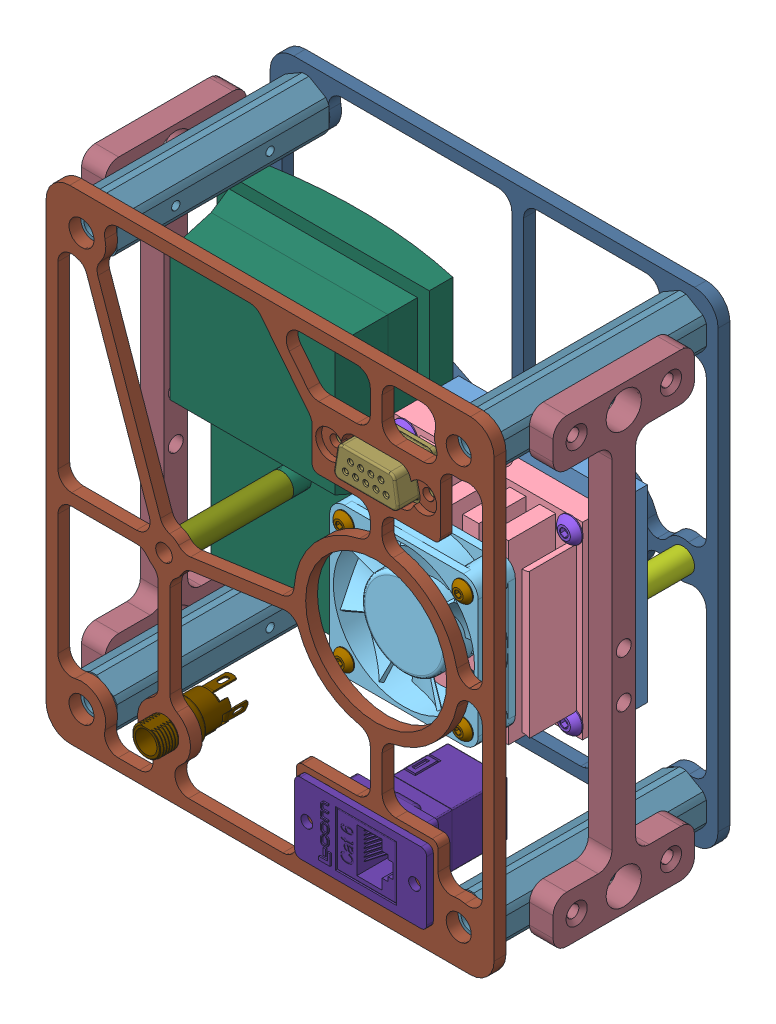
SolidWorks assembly Camera Module-Axis, configuration Default. Lengths in mm.
Overall size (127 130.18 68.59).
31 component instances, 18 part files, 40 mates.
Components (placement in the parent):
- Retina Fucker-1: Retina Fucker [Default] at (41.7658 96.3221 44.3342) x (-1 0 0) z (0 -1 0) size (51.1 57 52.54)
  - LED Interface Plate-1: LED Interface Plate [Default] at (13.1908 22.1092 31.2346) size (50.8 6.35 52.39)
  - Peltier Junction-1: Peltier Junction [Default] at (13.1908 17.3467 31.2346) size (39.69 4.76 39.69)
  - LZ4-40G108-0000-1: LZ4-40G108-0000 [Default] at (13.1908 28.4592 31.2346) size (19.46 5.4 19.4)
  - Heatsink-1: Heatsink [Default] at (13.1948 17.3467 31.2346) x (0 0 -1) z (-1 0 0) size (50.8 19.05 50.8)
  - 1939K170_DC EQUIPMENT COOLING FAN-1: 1939K170_DC EQUIPMENT COOLING FAN [Default] at (13.1908 -1.7033 31.2346) x (-0.000125 0 1) z (0 -1 0) size (40 40 10.64)
  - Reflector-1: Reflector [Default] at (13.1908 30.2092 31.2346) x (0.991681 0 -0.128723) z (0.128723 0 0.991681) size (16.67 13.5 16.67)
  - Front Mounting Spacer-1: Front Mounting Spacer [Default] at (-9.0342 28.4592 31.2346) x (1 0 0) z (0 1 0) size (6.35 6.35 12.7)
  - Front Mounting Spacer-2: Front Mounting Spacer [Default] at (13.1908 28.4592 53.4596) x (1 0 0) z (0 1 0) size (6.35 6.35 12.7)
  - Front Mounting Spacer-3: Front Mounting Spacer [Default] at (35.4158 28.4592 31.2346) x (1 0 0) z (0 1 0) size (6.35 6.35 12.7)
  - 91255A150_ALLOY STEEL BUTTON-HEAD SOCKET CAP SCREW 6-32 5_8-1: 91255A150_ALLOY STEEL BUTTON-HEAD SOCKET CAP SCREW 6-32 5_8 [91255A150] at (-9.0302 9.1425 9.0096) x (1 0 0) z (0 -1 0) size (6.65 6.65 18.16)
  - 91255A150_ALLOY STEEL BUTTON-HEAD SOCKET CAP SCREW 6-32 5_8-2: 91255A150_ALLOY STEEL BUTTON-HEAD SOCKET CAP SCREW 6-32 5_8 [91255A150] at (-9.0302 9.1425 53.4596) x (1 0 0) z (0 -1 0) size (6.65 6.65 18.16)
  - 91255A150_ALLOY STEEL BUTTON-HEAD SOCKET CAP SCREW 6-32 5_8-3: 91255A150_ALLOY STEEL BUTTON-HEAD SOCKET CAP SCREW 6-32 5_8 [91255A150] at (35.4198 9.1425 53.4596) x (1 0 0) z (0 -1 0) size (6.65 6.65 18.16)
  - 91255A150_ALLOY STEEL BUTTON-HEAD SOCKET CAP SCREW 6-32 5_8-4: 91255A150_ALLOY STEEL BUTTON-HEAD SOCKET CAP SCREW 6-32 5_8 [91255A150] at (35.4198 9.1425 9.0096) x (1 0 0) z (0 -1 0) size (6.65 6.65 18.16)
  - 91255A110_ALLOY STEEL BUTTON-HEAD SOCKET CAP SCREW 4-40 1_2-1: 91255A110_ALLOY STEEL BUTTON-HEAD SOCKET CAP SCREW 4-40 1_2 [91255A110] at (29.1928 -13.2019 15.2366) x (1 0 0) z (0 -1 0) size (5.41 5.41 14.54)
  - 91255A110_ALLOY STEEL BUTTON-HEAD SOCKET CAP SCREW 4-40 1_2-2: 91255A110_ALLOY STEEL BUTTON-HEAD SOCKET CAP SCREW 4-40 1_2 [91255A110] at (-2.8072 -13.2019 15.2326) x (1 0 0) z (0 -1 0) size (5.41 5.41 14.54)
  - 91255A110_ALLOY STEEL BUTTON-HEAD SOCKET CAP SCREW 4-40 1_2-3: 91255A110_ALLOY STEEL BUTTON-HEAD SOCKET CAP SCREW 4-40 1_2 [91255A110] at (29.1888 -13.2019 47.2366) x (1 0 0) z (0 -1 0) size (5.41 5.41 14.54)
  - 91255A110_ALLOY STEEL BUTTON-HEAD SOCKET CAP SCREW 4-40 1_2-4: 91255A110_ALLOY STEEL BUTTON-HEAD SOCKET CAP SCREW 4-40 1_2 [91255A110] at (-2.8112 -13.2019 47.2326) x (1 0 0) z (0 -1 0) size (5.41 5.41 14.54)
- Front Mounting Plate-Axis-1: Front Mounting Plate-Axis [Default] at (0 65.0875 3.175) x (0 1 0) z (0 0 -1) size (130.18 120.65 3.17)
- Back Mounting Plate-Axis-1: Back Mounting Plate-Axis [Default] at (0 65.0875 63.5) x (0 1 0) z (0 0 -1) size (130.18 120.65 3.17)
- COM DB-9 female-1: COM DB-9 female [По умолчанию] at (28.5782 104.775 59.825) x (-1 0 0) z (0 0 1) size (30 12.5 15.41)
- Side Mounting Plate-Axis-3: Side Mounting Plate-Axis [Default] at (57.15 65.0875 31.75) x (0 1 0) z (1 0 0) size (123.83 38.1 6.35)
- Side Mounting Plate-Axis-2: Side Mounting Plate-Axis [Default] at (-57.15 65.0875 31.75) x (0 1 0) z (-1 0 0) size (123.83 38.1 6.35)
- Camera Module Spacer-Axis-7: Camera Module Spacer-Axis [Default] at (50.8 120.65 31.75) x (0.866025 0.5 0) z (0 0 1) size (13.75 12.7 57.15)
- Camera Module Spacer-Axis-6: Camera Module Spacer-Axis [Default] at (50.8 9.525 31.75) x (0.866025 0.5 0) z (0 0 1) size (13.75 12.7 57.15)
- Camera Module Spacer-Axis-9: Camera Module Spacer-Axis [Default] at (-50.8 120.65 31.75) x (0.866025 0.5 0) z (0 0 1) size (13.75 12.7 57.15)
- Camera Module Spacer-Axis-8: Camera Module Spacer-Axis [Default] at (-50.8 9.525 31.75) x (0.866025 0.5 0) z (0 0 1) size (13.75 12.7 57.15)
- Axis M1013-1: Axis M1013 [Default] at (-28.575 82.55 11.1125) size (57.15 92.08 38.1)
- Axis Standoff-1: Axis Standoff [Default] at (-28.575 57.15 60.325) x (1 0 0) z (0 1 0) size (6.35 28.57 6.35)
- ECF504-SC6-1: ECF504-SC6 [Default] at (26.162 15.4305 65.278) x (0 1 0) z (0 0 1) size (19.05 35.56 30.51)
- L712A-1: L712A [Default] at (-28.575 15.4305 60.325) size (11.02 11.02 23.64)
Mates (geometry in assembly coordinates):
- Coincident5: coincident anti-aligned: plane of Retina Fucker-1/Front Mounting Spacer-2 through (28.575 42.8625 3.175) normal (0 0 -1); plane of Front Mounting Plate-Axis-1 through (0 65.0875 3.175) normal (0 0 1)
- Parallel1: parallel anti-aligned: plane of Retina Fucker-1/LED Interface Plate-1 through (3.175 90.4875 15.875) normal (0 1 0); plane of Front Mounting Plate-Axis-1 through (60.325 0 0) normal (0 -1 0)
- Concentric5: concentric anti-aligned: circle of Retina Fucker-1/Reflector-1; circle of Front Mounting Plate-Axis-1
- Coincident13: coincident anti-aligned: plane of Back Mounting Plate-Axis-1 through (0 65.0875 60.325) normal (0 0 -1); plane of COM DB-9 female-1 through (28.5782 104.775 60.325) normal (0 0 1)
- Concentric15: concentric anti-aligned: circle of COM DB-9 female-1; circle of Back Mounting Plate-Axis-1
- Coincident14: coincident anti-aligned: plane of Front Mounting Plate-Axis-1 through (0 65.0875 0) normal (0 0 -1); plane of assembly through (0 0 0) normal (0 0 1)
- Parallel4: parallel anti-aligned: plane of Back Mounting Plate-Axis-1 through (35.4584 99.441 60.325) normal (0 1 0); plane of COM DB-9 female-1 through (35.7376 100.525 66.325) normal (0 -1 0)
- Coincident20: coincident anti-aligned: plane of Front Mounting Plate-Axis-1 through (60.325 0 0) normal (0 -1 0); plane of assembly through (0 0 0) normal (0 1 0)
- Coincident21: coincident aligned: plane of Front Mounting Plate-Axis-1; plane of assembly through (0 0 0) normal (1 0 0)
- Coincident26: coincident aligned: plane of Front Mounting Plate-Axis-1; plane of Side Mounting Plate-Axis-3
- Coincident28: coincident anti-aligned: plane of Front Mounting Plate-Axis-1 through (0 65.0875 3.175) normal (0 0 1); plane of Camera Module Spacer-Axis-6 through (50.8 9.525 3.175) normal (0 0 -1)
- Concentric22: concentric anti-aligned: cylinder of Front Mounting Plate-Axis-1 through (50.8 9.525 0) axis (0 0 -1) radius 3.3782; cylinder of Camera Module Spacer-Axis-6 through (50.8 9.525 60.325) axis (0 0 1) radius 2.5527
- Concentric23: concentric anti-aligned: cylinder of Back Mounting Plate-Axis-1 through (50.8 9.525 60.325) axis (0 0 -1) radius 3.3782; cylinder of Camera Module Spacer-Axis-6 through (50.8 9.525 60.325) axis (0 0 1) radius 2.5527
- Coincident29: coincident anti-aligned: plane of Back Mounting Plate-Axis-1 through (0 65.0875 60.325) normal (0 0 -1); plane of Camera Module Spacer-Axis-6 through (50.8 9.525 60.325) normal (0 0 1)
- Coincident30: coincident anti-aligned: plane of Front Mounting Plate-Axis-1 through (0 65.0875 3.175) normal (0 0 1); plane of Camera Module Spacer-Axis-7 through (50.8 120.65 3.175) normal (0 0 -1)
- Concentric24: concentric anti-aligned: cylinder of Front Mounting Plate-Axis-1 through (50.8 120.65 0) axis (0 0 -1) radius 3.3782; cylinder of Camera Module Spacer-Axis-7 through (50.8 120.65 60.325) axis (0 0 1) radius 2.5527
- Coincident31: coincident anti-aligned: plane of Front Mounting Plate-Axis-1 through (0 65.0875 3.175) normal (0 0 1); plane of Camera Module Spacer-Axis-9 through (-50.8 120.65 3.175) normal (0 0 -1)
- Concentric25: concentric anti-aligned: cylinder of Back Mounting Plate-Axis-1 through (-50.8 120.65 60.325) axis (0 0 -1) radius 3.3782; cylinder of Camera Module Spacer-Axis-9 through (-50.8 120.65 60.325) axis (0 0 1) radius 2.5527
- Coincident32: coincident anti-aligned: plane of Front Mounting Plate-Axis-1 through (0 65.0875 3.175) normal (0 0 1); plane of Camera Module Spacer-Axis-8 through (-50.8 9.525 3.175) normal (0 0 -1)
- Concentric26: concentric anti-aligned: cylinder of Front Mounting Plate-Axis-1 through (-50.8 9.525 0) axis (0 0 -1) radius 3.3782; cylinder of Camera Module Spacer-Axis-8 through (-50.8 9.525 60.325) axis (0 0 1) radius 2.5527
- Coincident34: coincident aligned: plane of Camera Module Spacer-Axis-7 through (57.15 118.015 60.325) normal (1 0 0); plane of Camera Module Spacer-Axis-6 through (57.15 6.89 60.325) normal (1 0 0)
- Coincident35: coincident anti-aligned: plane of Camera Module Spacer-Axis-6 through (57.15 6.89 60.325) normal (1 0 0); plane of Side Mounting Plate-Axis-3 through (57.15 65.0875 31.75) normal (-1 0 0)
- Coincident36: coincident anti-aligned: plane of Camera Module Spacer-Axis-8 through (-57.15 12.16 60.325) normal (-1 0 0); plane of Side Mounting Plate-Axis-2 through (-57.15 65.0875 31.75) normal (1 0 0)
- Coincident37: coincident aligned: plane of Camera Module Spacer-Axis-9 through (-57.15 123.285 60.325) normal (-1 0 0); plane of Camera Module Spacer-Axis-8 through (-57.15 12.16 60.325) normal (-1 0 0)
- Concentric27: concentric anti-aligned: cylinder of Front Mounting Plate-Axis-1 through (-50.8 120.65 0) axis (0 0 -1) radius 3.3782; cylinder of Camera Module Spacer-Axis-9 through (-50.8 120.65 60.325) axis (0 0 1) radius 2.5527
- Parallel6: parallel anti-aligned: plane of Front Mounting Plate-Axis-1 through (0 65.0875 0) normal (0 0 -1); plane of Side Mounting Plate-Axis-2 through (-57.15 15.875 34.925) normal (0 0 1)
- Coincident39: coincident aligned: plane of Front Mounting Plate-Axis-1; plane of Side Mounting Plate-Axis-2
- Coincident40: coincident aligned: plane of Front Mounting Plate-Axis-1; plane of Side Mounting Plate-Axis-3
- Coincident41: coincident aligned: plane of Side Mounting Plate-Axis-3; plane of Camera Module Spacer-Axis-7 through (50.8 120.65 31.75) normal (0 0 1)
- Coincident42: coincident anti-aligned: plane of Side Mounting Plate-Axis-2; plane of Camera Module Spacer-Axis-7 through (50.8 120.65 31.75) normal (0 0 1)
- Distance1: distance = 1.5875 mm aligned: plane of Axis M1013-1 through (-28.575 89.8346 1.5875) normal (0 0 -1); plane of Front Mounting Plate-Axis-1 through (0 65.0875 0) normal (0 0 -1)
- Parallel7: parallel aligned: plane of Back Mounting Plate-Axis-1 through (-60.325 0 60.325) normal (-1 0 0); plane of Axis M1013-1 through (-57.15 19.05 14.2875) normal (-1 0 0)
- Distance2: distance = 19.05 mm aligned: plane of Axis M1013-1 through (-28.575 111.125 141.2875) normal (0 1 0); plane of Front Mounting Plate-Axis-1 through (60.325 130.175 0) normal (0 1 0)
- Distance3: distance = 3.175 mm anti-aligned: plane of Axis M1013-1 through (0 19.05 14.2875) normal (1 0 0); plane of Retina Fucker-1/LED Interface Plate-1 through (3.175 39.6875 15.875) normal (-1 0 0)
- Coincident47: coincident anti-aligned: plane of Back Mounting Plate-Axis-1 through (0 65.0875 60.325) normal (0 0 -1); plane of Axis Standoff-1 through (-28.575 57.15 60.325) normal (0 0 1)
- Concentric29: concentric anti-aligned: cylinder of Axis M1013-1 through (-28.575 57.15 40.7303) axis (0 0 -1) radius 3.175; cylinder of Axis Standoff-1 through (-28.575 57.15 31.75) axis (0 0 1) radius 3.175
- Coincident48: coincident anti-aligned: plane of Back Mounting Plate-Axis-1 through (0 65.0875 63.5) normal (0 0 1); plane of ECF504-SC6-1 through (42.418 7.4295 63.5) normal (0 0 -1)
- Coincident51: coincident anti-aligned: plane of Back Mounting Plate-Axis-1 through (0 65.0875 60.325) normal (0 0 -1); plane of L712A-1 through (-33.7058 15.4305 60.325) normal (0 0 1)
- Concentric30: concentric aligned: cylinder of Back Mounting Plate-Axis-1 through (-28.575 15.4305 63.5) axis (0 0 1) radius 3.9688; circle of L712A-1
- Concentric31: concentric anti-aligned: circle of Back Mounting Plate-Axis-1; circle of ECF504-SC6-1
